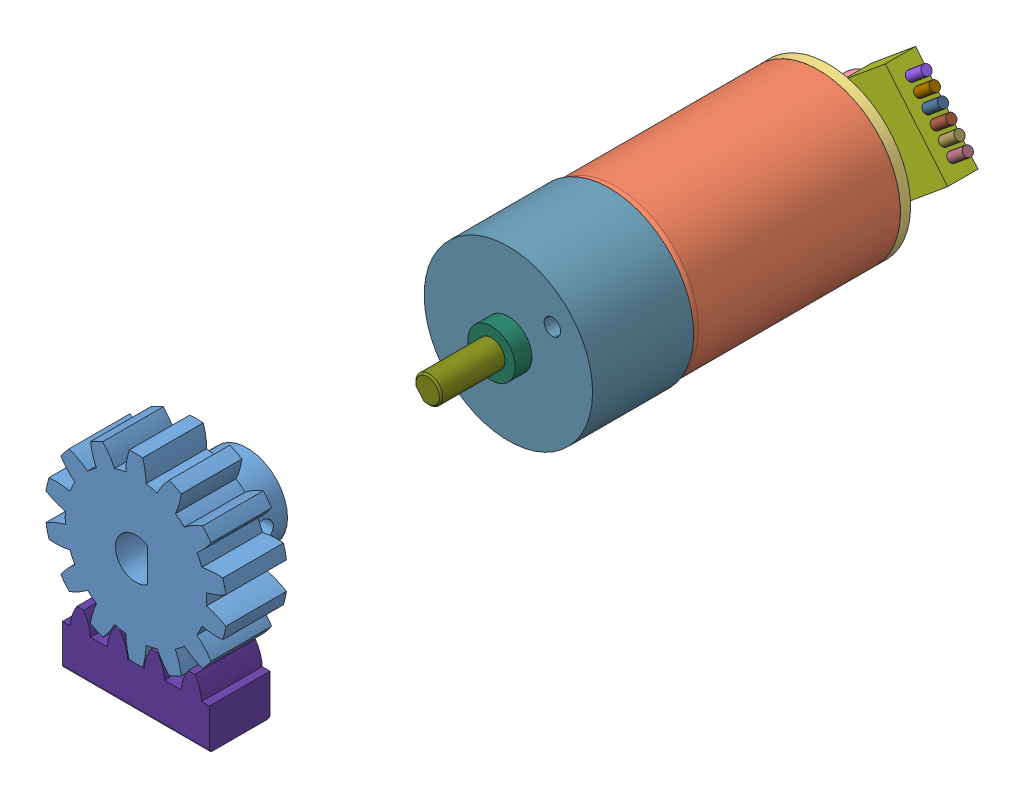
SolidWorks assembly rack n pinion, configuration Default. Lengths in mm.
Overall size (49.65 41.89 113.14).
18 component instances, 17 part files, 4 mates.
Components (placement in the parent):
- Gear RnP-1: Gear RnP [Default] at (1.6898 47.3601 -9.6445) size (26.7 27 16.5)
- JGA25-371_12VDC_915RPM.stp-1: JGA25-371_12VDC_915RPM.stp [Default] at (-22.5028 19.5308 -63.4328) x (0.638891 -0.769297 0) z (-0.769297 -0.638891 0) size (25 67 32.5)
  - JGA25-371_12VDC_915RPM1.stp-1: JGA25-371_12VDC_915RPM1.stp [Default] at origin size (24.4 31 24.4)
  - JGA25-371_12VDC_915RPM2.stp-1: JGA25-371_12VDC_915RPM2.stp [Default] at origin size (24.4 1.5 24.4)
  - JGA25-371_12VDC_915RPM3.stp-1: JGA25-371_12VDC_915RPM3.stp [Default] at origin size (14 7.5 14)
  - JGA25-371_12VDC_915RPM4.stp-1: JGA25-371_12VDC_915RPM4.stp [Default] at origin size (6.36 3.5 6.36)
  - JGA25-371_12VDC_915RPM5.stp-1: JGA25-371_12VDC_915RPM5.stp [Default] at origin size (6.36 3.5 6.36)
  - JGA25-371_12VDC_915RPM6.stp-1: JGA25-371_12VDC_915RPM6.stp [Default] at origin size (14.5 4.5 8.5)
  - JGA25-371_12VDC_915RPM7.stp-1: JGA25-371_12VDC_915RPM7.stp [Default] at origin size (1.4 1.4 3)
  - JGA25-371_12VDC_915RPM8.stp-1: JGA25-371_12VDC_915RPM8.stp [Default] at origin size (1.4 1.4 3)
  - JGA25-371_12VDC_915RPM9.stp-1: JGA25-371_12VDC_915RPM9.stp [Default] at origin size (1.4 1.4 3)
  - JGA25-371_12VDC_915RPM10.stp-1: JGA25-371_12VDC_915RPM10.stp [Default] at origin size (1.4 1.4 3)
  - JGA25-371_12VDC_915RPM11.stp-1: JGA25-371_12VDC_915RPM11.stp [Default] at origin size (1.4 1.4 3)
  - JGA25-371_12VDC_915RPM12.stp-1: JGA25-371_12VDC_915RPM12.stp [Default] at origin size (1.4 1.4 3)
  - JGA25-371_12VDC_915RPM13.stp-1: JGA25-371_12VDC_915RPM13.stp [Default] at origin size (25 15 25)
  - JGA25-371_12VDC_915RPM14.stp-1: JGA25-371_12VDC_915RPM14.stp [Default] at origin size (7 2.5 7)
  - JGA25-371_12VDC_915RPM15.stp-1: JGA25-371_12VDC_915RPM15.stp [Default] at origin size (4 9.5 4)
- Rack RnP-1: Rack RnP [Default] at (25.0851 40.8601 6.8555) size (36.37 9 14.7)
Mates (geometry in assembly coordinates):
- Concentric1: concentric anti-aligned: cylinder of Gear RnP-1 through (-22.5028 19.5308 -2.1445) axis (0 0 -1) radius 3.05; cylinder of JGA25-371_12VDC_915RPM.stp-1/JGA25-371_12VDC_915RPM15.stp-1 through (-22.5028 19.5308 -45.9328) axis (0 0 1) radius 2
- Coincident1: coincident aligned: plane of Gear RnP-1 through (1.6898 47.3601 6.8555) normal (0 0 1); plane of Rack RnP-1 through (25.0851 40.8601 6.8555) normal (0 0 1)
- Tangent2: tangent anti-aligned: cylinder of Gear RnP-1 through (-22.5028 19.5308 6.8555) axis (0 0 -1) radius 10.5; plane of Rack RnP-1 through (41.5851 9.0308 -6.3871) normal (0 1 0)
- Parallel1: parallel anti-aligned: plane of Rack RnP-1 through (25.0851 0.0308 -232.2228) normal (0 -1 0)
